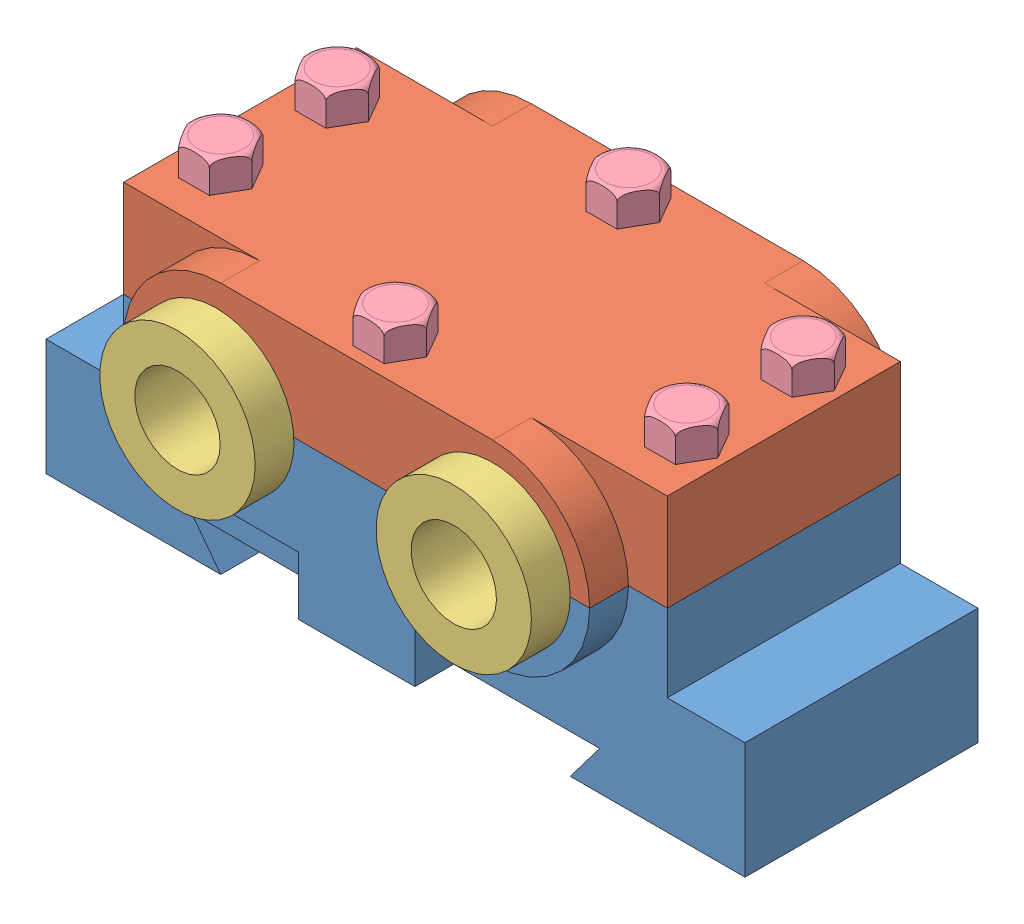
SolidWorks assembly Assem1, configuration Default. Lengths in mm.
Overall size (90 41.61 46.08).
10 component instances, 4 part files, 16 mates.
Components (placement in the parent):
- Part3-1: Part3 [Default] at (11.4229 51.5931 77.6395) size (90 25 40)
- Part4-1: Part4 [Default] at (11.4229 75.3431 77.6395) size (70 12.5 40)
- Part1-1: Part1 [Default] at (-6.0771 69.0931 100.7087) x (-0.684411 -0.729096 0) z (0.729096 -0.684411 0) size (20 45 20)
- Part1-2: Part1 [Default] at (28.9229 69.0931 100.1387) x (-0.93344 -0.358734 0) z (0.358734 -0.93344 0) size (20 45 20)
- Part2-1: Part2 [Default] at (-18.5771 83.5931 85.1395) x (1 0 0) z (0 0 -1) size (8.45 29.11 7.38)
- Part2-6: Part2 [Default] at (-18.5771 83.5931 70.1395) x (1 0 0) z (0 0 -1) size (8.45 29.11 7.38)
- Part2-7: Part2 [Default] at (41.4229 83.5931 85.1395) x (1 0 0) z (0 0 -1) size (8.45 29.11 7.38)
- Part2-8: Part2 [Default] at (41.4229 83.5931 70.1395) x (1 0 0) z (0 0 -1) size (8.45 29.11 7.38)
- Part2-9: Part2 [Default] at (11.4229 83.5931 92.6395) x (0.5 0 -0.866025) z (-0.866025 0 -0.5) size (8.45 29.11 7.38)
- Part2-11: Part2 [Default] at (11.4229 83.5931 62.6395) x (0.5 0 0.866025) z (0.866025 0 -0.5) size (8.45 29.11 7.38)
Mates (geometry in assembly coordinates):
- Coincident1: coincident anti-aligned: line of Part3-1 through (41.4229 69.0931 97.6395) axis (-1 0 0); line of Part4-1 through (36.4229 69.0931 97.6395) axis (1 0 0)
- Coincident2: coincident: plane of Part3-1 through (11.4229 69.0931 77.6395) normal (0 1 0); line of Part4-1 through (-18.5771 69.0931 97.6395) axis (1 0 0)
- Coincident3: coincident: line of Part3-1 through (41.4229 69.0931 57.6395) axis (0 0 1); cylinder of Part4-1 through (28.9229 69.0931 57.6395) axis (0 0 1) radius 12.5
- Concentric1: concentric aligned: cylinder of Part3-1 through (-6.0771 69.0931 57.6395) axis (0 0 1) radius 7.5; cylinder of Part1-1 through (-6.0771 69.0931 58.2087) axis (0 0 1) radius 7.5
- Concentric2: concentric aligned: circle of Part4-1; cylinder of Part1-1 through (-6.0771 69.0931 98.2087) axis (0 0 1) radius 10
- Concentric3: concentric aligned: cylinder of Part3-1 through (-6.0771 69.0931 57.6395) axis (0 0 1) radius 7.5; cylinder of Part1-1 through (-6.0771 69.0931 58.2087) axis (0 0 1) radius 7.5
- Coincident4: coincident aligned: circle of Part4-1; cylinder of Part1-1 through (-6.0771 69.0931 58.2087) axis (0 0 1) radius 7.5
- Concentric4: concentric aligned: cylinder of Part3-1 through (-6.0771 69.0931 57.6395) axis (0 0 1) radius 7.5; cylinder of Part1-1 through (-6.0771 69.0931 58.2087) axis (0 0 1) radius 7.5
- Concentric5: concentric aligned: circle of Part4-1; cylinder of Part1-2 through (28.9229 69.0931 97.6387) axis (0 0 1) radius 10
- Concentric6: concentric aligned: cylinder of Part3-1 through (28.9229 69.0931 57.6395) axis (0 0 1) radius 7.5; cylinder of Part1-2 through (28.9229 69.0931 57.6387) axis (0 0 1) radius 7.5
- Concentric7: concentric aligned: cylinder of Part4-1 through (-18.5771 69.0931 85.1395) axis (0 1 0) radius 2.25; cylinder of Part2-1 through (-18.5771 56.5931 85.1395) axis (0 1 0) radius 2.25
- Coincident5: coincident anti-aligned: plane of Part4-1 through (11.4229 81.5931 77.6395) normal (0 1 0); plane of Part2-1 through (-18.5771 81.5931 85.1395) normal (0 -1 0)
- Parallel1: parallel aligned: plane of Part4-1 through (-23.5771 81.5931 92.6395) normal (0 0 1); plane of Part2-1 through (-16.5771 81.5931 88.6036) normal (0 0 1)
- Concentric8: concentric aligned: cylinder of Part4-1 through (11.4229 69.0931 92.6395) axis (0 1 0) radius 2.25; cylinder of Part2-9 through (11.4229 56.5931 92.6395) axis (0 1 0) radius 2.25
- Coincident7: coincident anti-aligned: plane of Part4-1 through (11.4229 81.5931 77.6395) normal (0 1 0); plane of Part2-9 through (11.4229 81.5931 92.6395) normal (0 -1 0)
- Parallel2: parallel aligned: plane of Part4-1 through (11.4229 75.3431 97.6395) normal (0 0 1); plane of Part2-9 through (13.4229 81.5931 96.1036) normal (0 0 1)
